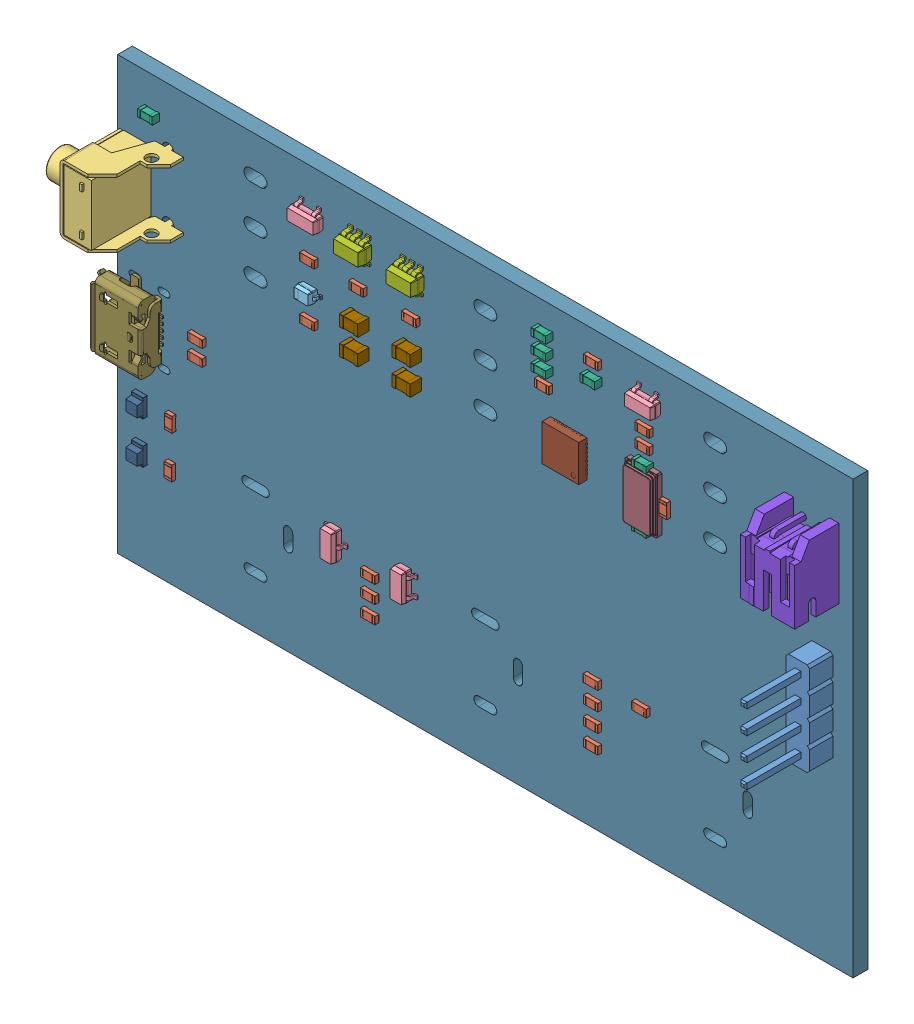
SolidWorks assembly ledTruck, configuration Default. Lengths in mm.
Overall size (82.71 47 12.53).
96 component instances, 14 part files, 0 mates.
Components (placement in the parent):
- ledTruck.step-1: ledTruck.step [Default] at origin size (82.71 47 12.53)
  - PinHeader_1x04_P2.54mm_Vertical.step-1: PinHeader_1x04_P2.54mm_Vertical.step [Default] at (76.5862 -26.2915 1.65) x (-1 0 0) z (0 0 1) size (2.54 10.16 11.54)
    - SOLID.step-1: SOLID.step [Default] at origin size (2.54 10.16 11.54)
  - R_0603_1608Metric.step-1: R_0603_1608Metric.step [Default] at (8.89 -22.225 1.65) x (-1 0 0) z (0 0 1) size (1.6 0.8 0.45)
    - SOLID-0.step-1: SOLID-0.step [Default] at origin size (1.6 0.8 0.45)
  - R_0603_1608Metric.step-2: R_0603_1608Metric.step [Default] at (8.89 -24.003 1.65) size (1.6 0.8 0.45)
    - SOLID-0.step-1: SOLID-0.step [Default] at origin size (1.6 0.8 0.45)
  - SW_Tactile_SPST_Angled_PTS645Vx58-2LFS.step-1: SW_Tactile_SPST_Angled_PTS645Vx58-2LFS.step [Default] at (3 -12 1.65) x (0 1 0) z (0 0 1) size (7.4 9.9 11)
    - SOLID-1.step-1: SOLID-1.step [Default] at origin size (7.4 9.9 11)
  - R_0603_1608Metric.step-3: R_0603_1608Metric.step [Default] at (26.416 -8.636 1.65) x (-1 0 0) z (0 0 1) size (1.6 0.8 0.45)
    - SOLID-0.step-1: SOLID-0.step [Default] at origin size (1.6 0.8 0.45)
  - R_0603_1608Metric.step-4: R_0603_1608Metric.step [Default] at (21.082 -14.478 1.65) size (1.6 0.8 0.45)
    - SOLID-0.step-1: SOLID-0.step [Default] at origin size (1.6 0.8 0.45)
  - R_0603_1608Metric.step-5: R_0603_1608Metric.step [Default] at (21.082 -8.636 1.65) x (-1 0 0) z (0 0 1) size (1.6 0.8 0.45)
    - SOLID-0.step-1: SOLID-0.step [Default] at origin size (1.6 0.8 0.45)
  - R_0603_1608Metric.step-6: R_0603_1608Metric.step [Default] at (27.686 -35.052 1.65) x (-1 0 0) z (0 0 1) size (1.6 0.8 0.45)
    - SOLID-0.step-1: SOLID-0.step [Default] at origin size (1.6 0.8 0.45)
  - SOT-23.step-1: SOT-23.step [Default] at (21.082 -4.572 1.65) x (0 -1 0) z (0 0 1) size (2.5 3 1.2)
    - SOLID-2.step-1: SOLID-2.step [Default] at origin size (2.5 3 1.2)
  - SOT-23.step-2: SOT-23.step [Default] at (31.496 -33.782 1.65) x (-1 0 0) z (0 0 1) size (2.5 3 1.2)
    - SOLID-2.step-1: SOLID-2.step [Default] at origin size (2.5 3 1.2)
  - SOT-23.step-3: SOT-23.step [Default] at (23.876 -33.782 1.65) size (2.5 3 1.2)
    - SOLID-2.step-1: SOLID-2.step [Default] at origin size (2.5 3 1.2)
  - D_SOD-323.step-1: D_SOD-323.step [Default] at (21.082 -11.684 1.65) size (2.5 1.25 1.1)
    - SOLID-3.step-1: SOLID-3.step [Default] at origin size (2.5 1.25 1.1)
  - C_0603_1608Metric.step-1: C_0603_1608Metric.step [Default] at (3.81 -3.556 1.65) size (1.6 0.8 0.8)
    - SOLID-4.step-1: SOLID-4.step [Default] at origin size (1.6 0.8 0.8)
  - R_0603_1608Metric.step-7: R_0603_1608Metric.step [Default] at (51.938 -2.799 1.65) size (1.6 0.8 0.45)
    - SOLID-0.step-1: SOLID-0.step [Default] at origin size (1.6 0.8 0.45)
  - SOT-23.step-4: SOT-23.step [Default] at (57.78 -3.688 1.65) x (0 -1 0) z (0 0 1) size (2.5 3 1.2)
    - SOLID-2.step-1: SOLID-2.step [Default] at origin size (2.5 3 1.2)
  - C_0603_1608Metric.step-2: C_0603_1608Metric.step [Default] at (51.938 -4.45 1.65) x (-1 0 0) z (0 0 1) size (1.6 0.8 0.8)
    - SOLID-4.step-1: SOLID-4.step [Default] at origin size (1.6 0.8 0.8)
  - SOT-23-5.step-1: SOT-23-5.step [Default] at (32.126 -4.704 1.65) x (0 -1 0) z (0 0 1) size (2.8 2.9 1.55)
    - SOLID-5.step-1: SOLID-5.step [Default] at origin size (2.8 2.9 1.55)
  - SOT-23-5.step-2: SOT-23-5.step [Default] at (26.416 -4.699 1.65) x (0 -1 0) z (0 0 1) size (2.8 2.9 1.55)
    - SOLID-5.step-1: SOLID-5.step [Default] at origin size (2.8 2.9 1.55)
  - JST_PH_S2B-PH-K_1x02_P2.00mm_Horizontal.step-1: JST_PH_S2B-PH-K_1x02_P2.00mm_Horizontal.step [Default] at (74.544 -6.228 1.65) size (5.9 7.6 8.25)
    - SOLID-6.step-1: SOLID-6.step [Default] at origin size (5.9 7.6 8.25)
  - R_0603_1608Metric.step-8: R_0603_1608Metric.step [Default] at (57.1958 -32.8676 1.65) x (-1 0 0) z (0 0 1) size (1.6 0.8 0.45)
    - SOLID-0.step-1: SOLID-0.step [Default] at origin size (1.6 0.8 0.45)
  - R_0603_1608Metric.step-9: R_0603_1608Metric.step [Default] at (57.526 -8.006 1.65) size (1.6 0.8 0.45)
    - SOLID-0.step-1: SOLID-0.step [Default] at origin size (1.6 0.8 0.45)
  - R_0603_1608Metric.step-10: R_0603_1608Metric.step [Default] at (57.526 -6.355 1.65) x (-1 0 0) z (0 0 1) size (1.6 0.8 0.45)
    - SOLID-0.step-1: SOLID-0.step [Default] at origin size (1.6 0.8 0.45)
  - R_0603_1608Metric.step-11: R_0603_1608Metric.step [Default] at (5.969 -36.068 1.65) x (0 -1 0) z (0 0 1) size (1.6 0.8 0.45)
    - SOLID-0.step-1: SOLID-0.step [Default] at origin size (1.6 0.8 0.45)
  - R_0603_1608Metric.step-12: R_0603_1608Metric.step [Default] at (5.9944 -31.4706 1.65) x (0 1 0) z (0 0 1) size (1.6 0.8 0.45)
    - SOLID-0.step-1: SOLID-0.step [Default] at origin size (1.6 0.8 0.45)
  - R_0603_1608Metric.step-13: R_0603_1608Metric.step [Default] at (46.604 -7.752 1.65) size (1.6 0.8 0.45)
    - SOLID-0.step-1: SOLID-0.step [Default] at origin size (1.6 0.8 0.45)
  - R_0603_1608Metric.step-14: R_0603_1608Metric.step [Default] at (59.812 -12.705 1.65) x (0 1 0) z (0 0 1) size (1.6 0.8 0.45)
    - SOLID-0.step-1: SOLID-0.step [Default] at origin size (1.6 0.8 0.45)
  - R_0603_1608Metric.step-15: R_0603_1608Metric.step [Default] at (32.1514 -8.636 1.65) x (-1 0 0) z (0 0 1) size (1.6 0.8 0.45)
    - SOLID-0.step-1: SOLID-0.step [Default] at origin size (1.6 0.8 0.45)
  - R_0603_1608Metric.step-16: R_0603_1608Metric.step [Default] at (51.938 -38.994 1.65) x (-1 0 0) z (0 0 1) size (1.6 0.8 0.45)
    - SOLID-0.step-1: SOLID-0.step [Default] at origin size (1.6 0.8 0.45)
  - R_0603_1608Metric.step-17: R_0603_1608Metric.step [Default] at (51.938 -34.93 1.65) size (1.6 0.8 0.45)
    - SOLID-0.step-1: SOLID-0.step [Default] at origin size (1.6 0.8 0.45)
  - R_0603_1608Metric.step-18: R_0603_1608Metric.step [Default] at (27.686 -36.957 1.65) size (1.6 0.8 0.45)
    - SOLID-0.step-1: SOLID-0.step [Default] at origin size (1.6 0.8 0.45)
  - R_0603_1608Metric.step-19: R_0603_1608Metric.step [Default] at (51.938 -36.962 1.65) x (-1 0 0) z (0 0 1) size (1.6 0.8 0.45)
    - SOLID-0.step-1: SOLID-0.step [Default] at origin size (1.6 0.8 0.45)
  - R_0603_1608Metric.step-20: R_0603_1608Metric.step [Default] at (51.9176 -32.9184 1.65) x (-1 0 0) z (0 0 1) size (1.6 0.8 0.45)
    - SOLID-0.step-1: SOLID-0.step [Default] at origin size (1.6 0.8 0.45)
  - R_0603_1608Metric.step-21: R_0603_1608Metric.step [Default] at (27.686 -38.862 1.65) size (1.6 0.8 0.45)
    - SOLID-0.step-1: SOLID-0.step [Default] at origin size (1.6 0.8 0.45)
  - C_0805_2012Metric.step-1: C_0805_2012Metric.step [Default] at (26.416 -14.478 1.65) x (-1 0 0) z (0 0 1) size (2 1.25 1.25)
    - SOLID-7.step-1: SOLID-7.step [Default] at origin size (2 1.25 1.25)
  - C_0603_1608Metric.step-3: C_0603_1608Metric.step [Default] at (46.604 -6.101 1.65) x (-1 0 0) z (0 0 1) size (1.6 0.8 0.8)
    - SOLID-4.step-1: SOLID-4.step [Default] at origin size (1.6 0.8 0.8)
  - C_0805_2012Metric.step-2: C_0805_2012Metric.step [Default] at (32.126 -11.689 1.65) size (2 1.25 1.25)
    - SOLID-7.step-1: SOLID-7.step [Default] at origin size (2 1.25 1.25)
  - C_0603_1608Metric.step-4: C_0603_1608Metric.step [Default] at (46.604 -4.45 1.65) size (1.6 0.8 0.8)
    - SOLID-4.step-1: SOLID-4.step [Default] at origin size (1.6 0.8 0.8)
  - C_0603_1608Metric.step-5: C_0603_1608Metric.step [Default] at (46.604 -2.799 1.65) size (1.6 0.8 0.8)
    - SOLID-4.step-1: SOLID-4.step [Default] at origin size (1.6 0.8 0.8)
  - C_0805_2012Metric.step-3: C_0805_2012Metric.step [Default] at (26.416 -11.684 1.65) x (-1 0 0) z (0 0 1) size (2 1.25 1.25)
    - SOLID-7.step-1: SOLID-7.step [Default] at origin size (2 1.25 1.25)
  - C_0603_1608Metric.step-6: C_0603_1608Metric.step [Default] at (57.526 -9.657 1.65) size (1.6 0.8 0.8)
    - SOLID-4.step-1: SOLID-4.step [Default] at origin size (1.6 0.8 0.8)
  - C_0603_1608Metric.step-7: C_0603_1608Metric.step [Default] at (57.526 -15.626 1.65) size (1.6 0.8 0.8)
    - SOLID-4.step-1: SOLID-4.step [Default] at origin size (1.6 0.8 0.8)
  - C_0805_2012Metric.step-4: C_0805_2012Metric.step [Default] at (32.126 -14.478 1.65) size (2 1.25 1.25)
    - SOLID-7.step-1: SOLID-7.step [Default] at origin size (2 1.25 1.25)
  - LED_0805_2012Metric.step-1: LED_0805_2012Metric.step [Default] at (2.6589 -36 1.65) x (0 -1 0) z (0 0 1) size (2 1.25 1.1)
    - SOLID-8.step-1: SOLID-8.step [Default] at origin size (2 1.25 1.1)
  - LED_0805_2012Metric.step-2: LED_0805_2012Metric.step [Default] at (2.6589 -31.45 1.65) x (0 -1 0) z (0 0 1) size (2 1.25 1.1)
    - SOLID-8.step-1: SOLID-8.step [Default] at origin size (2 1.25 1.1)
  - QFN-32-1EP_4x4mm_P0.4mm_EP2.65x2.65mm.step-1: QFN-32-1EP_4x4mm_P0.4mm_EP2.65x2.65mm.step [Default] at (49.136 -12.5 1.65) x (-1 0 0) z (0 0 1) size (4 4 0.92)
    - SOLID-9.step-1: SOLID-9.step [Default] at origin size (4 4 0.92)
  - USB_Micro-B_Molex_47346-0001.step-1: USB_Micro-B_Molex_47346-0001.step [Default] at (3.3873 -23.4924 1.65) x (0 -1 0) z (0 0 1) size (7.98 5.42 2.94)
    - SOLID-10.step-1: SOLID-10.step [Default] at origin size (7.98 5.42 2.94)
  - Crystal_SMD_0603-4Pin_6.0x3.5mm.step-1: Crystal_SMD_0603-4Pin_6.0x3.5mm.step [Default] at (57.526 -12.705 1.65) x (0 1 0) z (0 0 1) size (6 3.5 1.03)
    - SOLID-11.step-1: SOLID-11.step [Default] at origin size (6 3.5 1.03)
  - COMPOUND.step-1: COMPOUND.step [Default] at origin size (80 47 1.6)
